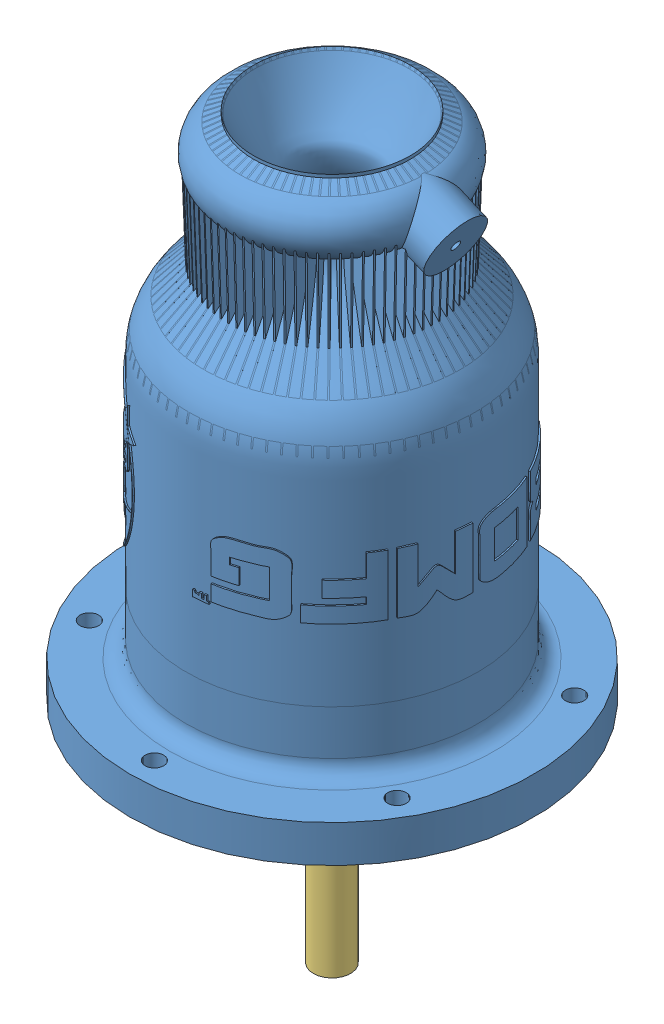
SolidWorks assembly Assembly_Engine_Pintle_V1, configuration Default. Lengths in mm.
Overall size (137.73 251.9 137.73).
3 component instances, 3 part files, 3 mates.
Components (placement in the parent):
- Part_Engine_V1-1: Part_Engine_V1 [Default] at origin size (137.73 174.49 137.73)
- Part_Pintle_V1-1: Part_Pintle_V1 [Default] at (0 -117.528 0) x (1 0 0) z (0 0 -1) size (35.56 53.02 35.56)
- Part_SSTube-1: Part_SSTube [Default] at (0 -229.5068 0) size (12.7 76.2 12.7)
Mates (geometry in assembly coordinates):
- Coincident1: coincident anti-aligned: plane of Part_Engine_V1-1 through (47.9109 -146.9568 0) normal (0 -1 0); plane of Part_Pintle_V1-1 through (0 -146.9568 0) normal (0 1 0)
- Concentric1: concentric anti-aligned: circle of Part_Pintle_V1-1; circle of Part_SSTube-1
- Coincident2: coincident anti-aligned: plane of Part_Pintle_V1-1 through (0 -153.3068 0) normal (0 -1 0); plane of Part_SSTube-1 through (0 -153.3068 0) normal (0 1 0)
